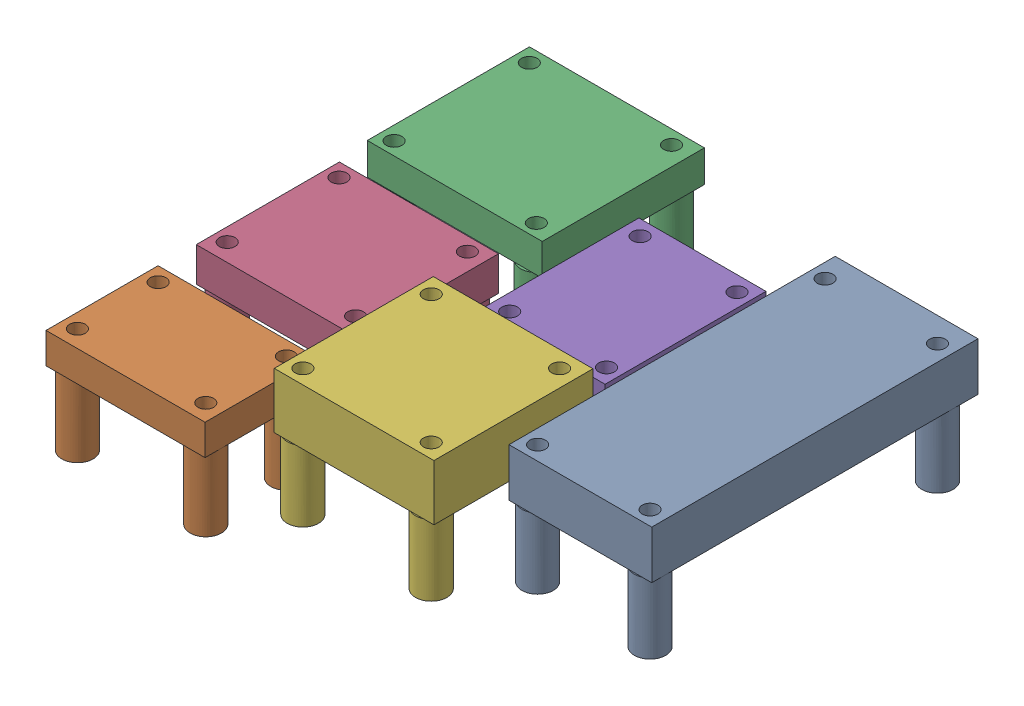
SolidWorks assembly EBoard_NEW, configuration Default. Lengths in mm.
Overall size (78.85 20.19 78.3).
7 component instances, 7 part files, 6 mates.
Components (placement in the parent):
- Base_NEW-1: Base_NEW [Default] at (73.9878 -8.2784 30.469) (suppressed, hidden)
- RP2-B2_NEW-2: RP2-B2_NEW [Default] at (24.2475 5.209 8.0845) x (0 0 -1) z (1 0 0) size (52.31 18.92 23.01)
- BME680_NEW-1: BME680_NEW [Default] at (-25.2951 5.844 37.5304) size (25.61 16.76 18.11)
- QWIIC OpenLog_NEW-1: QWIIC OpenLog_NEW [Default] at (-31.6945 5.463 -23.4413) size (28.24 16.56 26.59)
- BN008x 900F_NEW-1: BN008x 900F_NEW [Default] at (-8.2632 4.9822 -1.3723) size (25.78 16.49 23.18)
- MAX 17048_NEW-1: MAX 17048_NEW [Default] at (-1.5796 2.6944 -11.2533) size (20.6 16.38 25.83)
- GPS_NEW-1: GPS_NEW [Default] at (1.6099 5.2852 20.4854) size (25.71 20.19 25.61)
Mates (geometry in assembly coordinates):
- Coincident1: coincident anti-aligned: circle of RP2-B2_NEW-2; plane of Base_NEW-1 through (73.9878 -6.0178 30.469) normal (0 1 0)
- Coincident2: coincident anti-aligned: circle of QWIIC OpenLog_NEW-1; plane of Base_NEW-1 through (73.9878 -6.0178 30.469) normal (0 1 0)
- Coincident3: coincident anti-aligned: plane of Base_NEW-1 through (73.9878 -6.0178 30.469) normal (0 1 0); circle of MAX 17048_NEW-1
- Coincident6: coincident anti-aligned: plane of Base_NEW-1 through (73.9878 -6.0178 30.469) normal (0 1 0); circle of GPS_NEW-1
- Coincident9: coincident anti-aligned: plane of Base_NEW-1 through (73.9878 -6.0178 30.469) normal (0 1 0); circle of BN008x 900F_NEW-1
- Coincident10: coincident anti-aligned: plane of Base_NEW-1 through (73.9878 -6.0178 30.469) normal (0 1 0); circle of BME680_NEW-1
